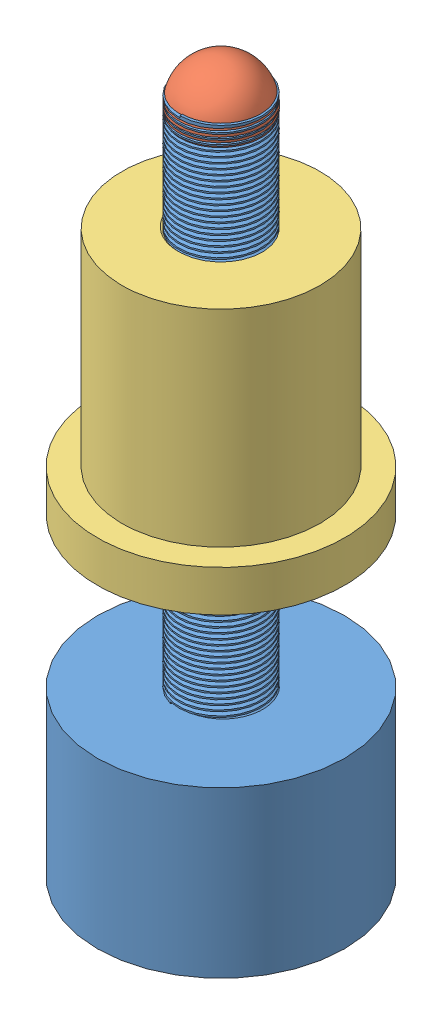
SolidWorks assembly ScrewSet, configuration Default. Lengths in mm.
Overall size (12.55 34.44 12.55).
3 component instances, 3 part files, 1 mates.
Components (placement in the parent):
- Screw-1: Screw [Default] at (10.546 3.3879 24.5417) size (12 33.09 12)
- Bearing-1: Bearing [Default] at (10.5106 35.8286 24.4998) size (4 4 4)
- BrassHolder-1: BrassHolder [Default] at (10.546 18.6519 24.5417) x (0.9989 0 -0.046895) z (0.046895 0 0.9989) size (12 12.13 12)
Mates (geometry in assembly coordinates):
- Tangent1: tangent: curve of Screw-1; cylinder of BrassHolder-1 through (10.546 18.6519 24.5417) axis (0 1 0) radius 2
